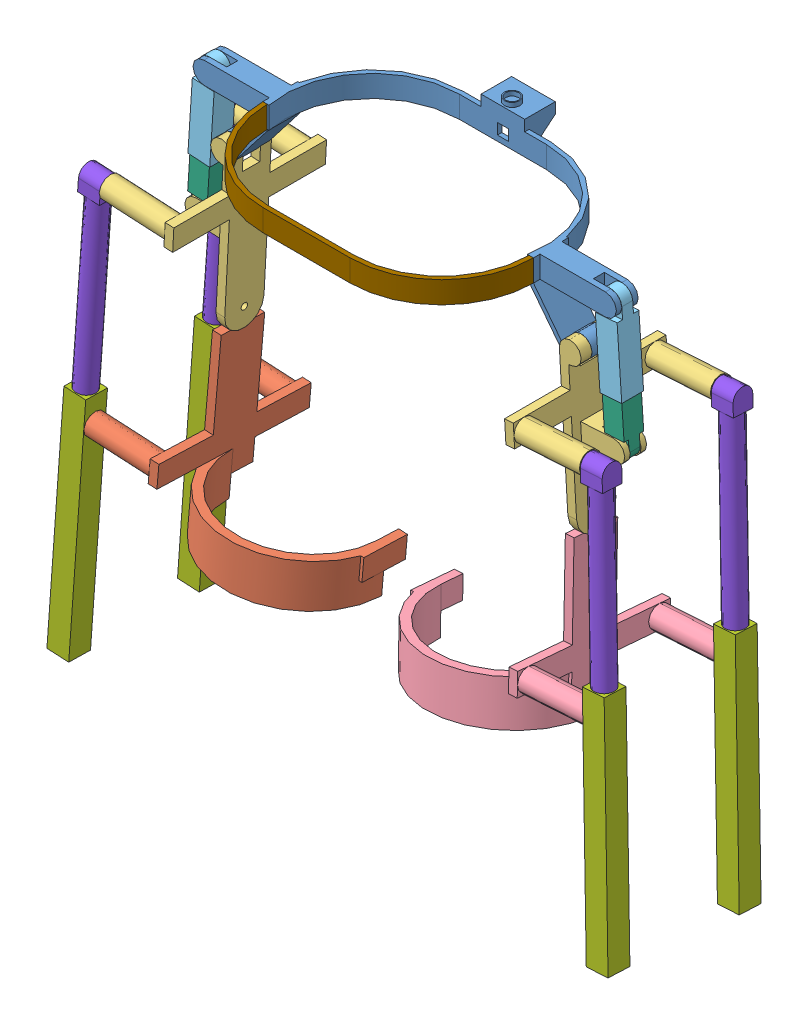
SolidWorks assembly waist, configuration Default. Lengths in mm.
Overall size (523.47 492.8 208).
18 component instances, 9 part files, 38 mates.
Components (placement in the parent):
- waist_p1_unit-1: waist_p1_unit [Default] at (141.338 215.4433 308.4147) size (388 80.32 124)
- waist_leg_right-1: waist_leg_right [Default] at (42.2989 -108.4338 314.3706) x (-0.998568 0.053498 0) z (-0.001992 -0.037184 -0.999306) size (208 140 144)
- waist_leg_p1-1: waist_leg_p1 [Default] at (-15.3736 48.7699 308.6361) x (-0.998568 0.053498 0) z (0 0 -1) size (68 158 140)
- waist_leg_p1-2: waist_leg_p1 [Default] at (298.8769 48.7533 308.4147) x (0.998208 0.059835 0) z (0 0 1) size (68 158 140)
- waist_leg_left-1: waist_leg_left [Default] at (242.1804 -108.4303 320.6966) x (-0.998208 -0.059835 0) z (0.004772 -0.079609 -0.996815) size (208 140 144)
- waist_leg_pole_2_a-1: waist_leg_pole_2_a [Default] at (326.1637 213.4717 308.4147) x (0 0 1) z (0.99763 0.068807 0) size (20 82 20)
- waist_leg_pole_2_b-1: waist_leg_pole_2_b [Default] at (332.411 122.8922 308.4147) x (0 0 1) z (-0.99763 -0.068807 0) size (18 79 18)
- waist_rod_a-1: waist_rod_a [Default] at (393.15 -220.3905 263.9913) x (-0.998208 -0.059835 0) z (-0.05978 0.997297 -0.042718) size (20 20 212)
- waist_rod_b-1: waist_rod_b [Default] at (370.814 152.2348 248.0302) x (0.998208 0.059835 0) z (0.002556 -0.042642 -0.999087) size (20 220 18)
- waist_rod_a-2: waist_rod_a [Default] at (-107.8203 -218.7966 255.8621) x (0.998568 -0.053498 0) z (0.053487 0.998369 -0.01995) size (20 20 212)
- waist_rod_b-2: waist_rod_b [Default] at (-87.9657 151.7992 248.4565) x (0.998568 -0.053498 0) z (-0.001067 -0.019922 -0.999801) size (20 220 18)
- waist_rod_a-3: waist_rod_a [Default] at (-107.5812 -214.3345 375.784) x (0.998568 -0.053498 0) z (0.053487 0.998369 -0.019981) size (20 20 212)
- waist_rod_b-3: waist_rod_b [Default] at (-87.9657 151.7992 368.4562) x (0.998568 -0.053498 0) z (-0.001069 -0.019953 -0.9998) size (20 220 18)
- waist_rod_a-4: waist_rod_a [Default] at (392.5773 -210.8363 383.6327) x (-0.998208 -0.059835 0) z (-0.05978 0.997291 -0.042861) size (20 20 212)
- waist_rod_b-4: waist_rod_b [Default] at (370.814 152.2347 368.029) x (0.998208 0.059835 0) z (0.002565 -0.042784 -0.999081) size (20 220 18)
- waist_leg_pole_2_a-2: waist_leg_pole_2_a [Default] at (-43.4418 213.4686 308.4147) x (0 0 1) z (0.997887 -0.064976 0) size (20 82 20)
- waist_leg_pole_2_b-2: waist_leg_pole_2_b [Default] at (-49.3525 122.6929 308.6361) x (0 0 1) z (-0.997887 0.064976 0) size (18 79 18)
- front_a-1: front_a [Default] at (141.338 215.4433 324.4147) size (248 20 84)
Mates (geometry in assembly coordinates):
- 同心5: concentric aligned: cylinder of waist_leg_right-1 through (-23.3621 49.1979 308.6361) axis (0.998568 -0.053498 0) radius 18; cylinder of waist_leg_p1-1 through (-23.3621 49.1979 308.6361) axis (0.998568 -0.053498 0) radius 18
- 重合4: coincident aligned: plane of waist_leg_right-1 through (-29.4168 -63.8163 332.8672) normal (-0.998568 0.053498 0); plane of waist_leg_p1-1 through (-18.0123 149.0547 238.6361) normal (-0.998568 0.053498 0)
- 同心6: concentric anti-aligned: cylinder of waist_leg_p1-2 through (306.8626 49.2319 308.4147) axis (-0.998208 -0.059835 0) radius 18; cylinder of waist_leg_left-1 through (159.1277 40.3764 308.4147) axis (0.998208 0.059835 0) radius 18
- 重合5: coincident aligned: plane of waist_leg_p1-2 through (300.8791 149.0528 378.4147) normal (0.998208 0.059835 0); plane of waist_leg_left-1 through (313.5666 -62.6091 337.4428) normal (0.998208 0.059835 0)
- 重合8: coincident anti-aligned: plane of waist_leg_pole_2_a-1 through (321.3134 152.9946 299.4147) normal (0.99763 0.068807 0); plane of waist_leg_pole_2_b-1 through (319.3039 182.1307 299.4147) normal (-0.99763 -0.068807 0)
- 同心16: concentric anti-aligned: cylinder of waist_leg_p1-1 through (-78.4614 142.2789 248.6361) axis (0.998568 -0.053498 0) radius 10; cylinder of waist_rod_b-2 through (1.424 137.999 248.6361) axis (-0.998568 0.053498 0) radius 9
- 重合12: coincident anti-aligned: plane of waist_leg_p1-1 through (-78.4614 142.2789 248.6361) normal (-0.998568 0.053498 0); plane of waist_rod_b-2 through (-79.0401 131.4761 257.8537) normal (0.998568 -0.053498 0)
- 重合13: coincident anti-aligned: plane of waist_leg_right-1 through (-88.9557 -53.6023 252.5503) normal (-0.998568 0.053498 0); plane of waist_rod_a-2 through (-87.6827 -29.8407 242.0735) normal (0.998568 -0.053498 0)
- 同心18: concentric aligned: cylinder of waist_leg_right-1 through (-88.9557 -53.6023 252.5503) axis (0.998568 -0.053498 0) radius 10; cylinder of waist_rod_a-2 through (-98.9414 -53.0674 252.5503) axis (0.998568 -0.053498 0) radius 3
- 同心19: concentric anti-aligned: cylinder of waist_rod_a-2 through (-97.6577 -29.1065 252.0715) axis (-0.053487 -0.998369 0.01995) radius 9; cylinder of waist_rod_b-2 through (-99.7329 -67.8421 252.8456) axis (0.053487 0.998369 -0.01995) radius 9
- 同心20: concentric anti-aligned: cylinder of waist_leg_p1-1 through (-78.4614 142.2789 368.6361) axis (0.998568 -0.053498 0) radius 10; cylinder of waist_rod_b-3 through (1.424 137.999 368.6361) axis (-0.998568 0.053498 0) radius 9
- 重合14: coincident anti-aligned: plane of waist_leg_p1-1 through (-78.4614 142.2789 368.6361) normal (-0.998568 0.053498 0); plane of waist_rod_b-3 through (-79.0401 131.4764 377.8541) normal (0.998568 -0.053498 0)
- 同心21: concentric aligned: cylinder of waist_leg_right-1 through (-88.7166 -49.1403 372.4671) axis (0.998568 -0.053498 0) radius 10; cylinder of waist_rod_a-3 through (-98.7023 -48.6053 372.4671) axis (0.998568 -0.053498 0) radius 3
- 重合15: coincident anti-aligned: plane of waist_leg_right-1 through (-88.7166 -49.1403 372.4671) normal (-0.998568 0.053498 0); plane of waist_rod_a-3 through (-87.4436 -25.3789 361.9896) normal (0.998568 -0.053498 0)
- 同心22: concentric anti-aligned: cylinder of waist_rod_a-3 through (-97.4186 -24.6444 371.9876) axis (-0.053487 -0.998369 0.019981) radius 9; cylinder of waist_rod_b-3 through (-99.7329 -67.8419 372.8521) axis (0.053487 0.998369 -0.019981) radius 9
- 同心23: concentric aligned: cylinder of waist_leg_p1-2 through (361.3699 142.6608 248.4147) axis (-0.998208 -0.059835 0) radius 10; cylinder of waist_rod_b-1 through (461.1908 148.6443 248.4147) axis (-0.998208 -0.059835 0) radius 9
- 重合16: coincident anti-aligned: plane of waist_leg_p1-2 through (361.3699 142.6608 248.4147) normal (0.998208 0.059835 0); plane of waist_rod_b-1 through (362.0045 132.0743 257.8764) normal (-0.998208 -0.059835 0)
- 同心24: concentric aligned: cylinder of waist_leg_left-1 through (373.2444 -55.4375 256.9001) axis (-0.998208 -0.059835 0) radius 10; cylinder of waist_rod_a-1 through (383.2265 -54.8392 256.9001) axis (-0.998208 -0.059835 0) radius 3
- 同心25: concentric anti-aligned: cylinder of waist_rod_a-1 through (381.7917 -30.904 255.8748) axis (0.05978 -0.997297 0.042718) radius 9; cylinder of waist_rod_b-1 through (383.9656 -67.1706 257.4283) axis (-0.05978 0.997297 -0.042718) radius 9
- 同心27: concentric aligned: cylinder of waist_leg_left-1 through (372.6717 -45.8844 376.5178) axis (-0.998208 -0.059835 0) radius 10; cylinder of waist_rod_a-4 through (382.6538 -45.286 376.5178) axis (-0.998208 -0.059835 0) radius 3
- 重合18: coincident anti-aligned: plane of waist_leg_left-1 through (372.6717 -45.8844 376.5178) normal (0.998208 0.059835 0); plane of waist_rod_a-4 through (371.2114 -21.5216 385.48) normal (-0.998208 -0.059835 0)
- 同心29: concentric anti-aligned: cylinder of waist_rod_a-4 through (381.2191 -21.3511 375.4892) axis (0.05978 -0.997291 0.042861) radius 9; cylinder of waist_rod_b-4 through (383.9656 -67.1693 377.4583) axis (-0.05978 0.997291 -0.042861) radius 9
- 重合19: coincident anti-aligned: plane of waist_p1_unit-1 through (335.338 215.4433 303.4147) normal (0 0 1); plane of waist_leg_pole_2_a-1 through (325.338 225.4433 303.4147) normal (0 0 -1)
- 同心32: concentric anti-aligned: cylinder of waist_p1_unit-1 through (301.0805 179.1187 316.4147) axis (0 0 -1) radius 10; cylinder of waist_leg_p1-2 through (301.0805 179.1187 238.4147) axis (0 0 1) radius 10
- 重合21: coincident anti-aligned: plane of waist_p1_unit-1 through (301.0805 179.1187 300.4147) normal (0 0 -1); plane of waist_leg_p1-2 through (429.6946 206.1312 300.4147) normal (0 0 1)
- 同心34: concentric aligned: cylinder of waist_leg_p1-2 through (361.3699 142.6608 368.4147) axis (-0.998208 -0.059835 0) radius 10; cylinder of waist_rod_b-4 through (461.1908 148.6443 368.4147) axis (-0.998208 -0.059835 0) radius 9
- 重合22: coincident anti-aligned: plane of waist_leg_pole_2_a-1 through (321.3134 152.9946 299.4147) normal (0 0 1); plane of waist_leg_pole_2_b-1 through (337.2612 183.3693 299.4147) normal (0 0 -1)
- 同心36: concentric aligned: cylinder of waist_leg_p1-2 through (333.0991 112.9159 338.4147) axis (0 0 -1) radius 10; cylinder of waist_leg_pole_2_b-1 through (333.0991 112.9159 313.4147) axis (0 0 -1) radius 9
- 同心37: concentric anti-aligned: cylinder of waist_p1_unit-1 through (325.338 225.4433 224.4147) axis (0 0 1) radius 10; cylinder of waist_leg_pole_2_a-1 through (325.338 225.4433 313.4147) axis (0 0 -1) radius 10
- 同心40: concentric aligned: cylinder of waist_p1_unit-1 through (-18.4045 179.1187 316.4147) axis (0 0 -1) radius 10; cylinder of waist_leg_p1-1 through (-18.4045 179.1187 378.6361) axis (0 0 -1) radius 10
- 同心41: concentric anti-aligned: cylinder of waist_leg_p1-1 through (-50.0023 112.714 278.6361) axis (0 0 1) radius 10; cylinder of waist_leg_pole_2_b-2 through (-50.0023 112.714 313.6361) axis (0 0 -1) radius 9
- 重合23: coincident anti-aligned: plane of waist_leg_p1-1 through (-15.3736 48.7699 303.6361) normal (0 0 1); plane of waist_leg_pole_2_b-2 through (-50.0023 112.714 303.6361) normal (0 0 -1)
- 同心42: concentric anti-aligned: cylinder of waist_p1_unit-1 through (-42.662 225.4433 224.4147) axis (0 0 1) radius 10; cylinder of waist_leg_pole_2_a-2 through (-42.662 225.4433 313.4147) axis (0 0 -1) radius 10
- 重合24: coincident anti-aligned: plane of waist_p1_unit-1 through (-52.662 215.4433 303.4147) normal (0 0 1); plane of waist_leg_pole_2_a-2 through (-42.662 225.4433 303.4147) normal (0 0 -1)
- 重合25: coincident anti-aligned: plane of waist_leg_pole_2_a-2 through (-56.3213 154.1802 299.4147) normal (0.997887 -0.064976 0); plane of waist_leg_pole_2_b-2 through (-54.4349 183.1509 299.6361) normal (-0.997887 0.064976 0)
- 重合26: coincident: plane of waist_p1_unit-1 through (17.338 235.4433 324.4147) normal (0 0 1); plane of front_a-1 through (24.0742 235.4433 324.4147) normal (0 0 -1)
- 重合27: coincident: plane of waist_p1_unit-1 through (101.338 235.4433 308.4147) normal (0 1 0); plane of front_a-1 through (188.0742 235.4433 324.4147) normal (0 1 0)
- 重合28: coincident: plane of waist_p1_unit-1 through (17.338 235.4433 292.4147) normal (-1 0 0); line of front_a-1 through (17.338 235.4433 324.4147) axis (0 -1 0)
